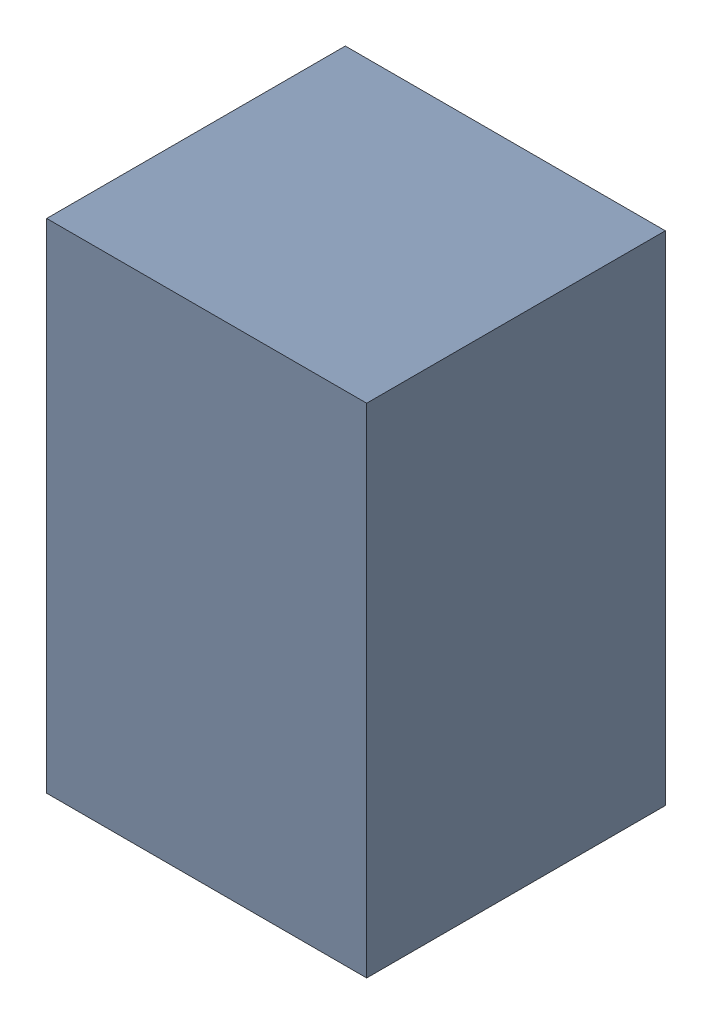
SolidWorks assembly C31, configuration Default. Lengths in mm.
Overall size (1.35 2.1 1.26).
2 component instances, 1 part files, 0 mates.
Components (placement in the parent):
- 407985696-1: 407985696 [Default] at (33.782 34.163 0.0127) size (1.35 2.1 1.26)
  - Extruded_1-1: Extruded_1 [Default] at origin size (1.35 2.1 1.26)
